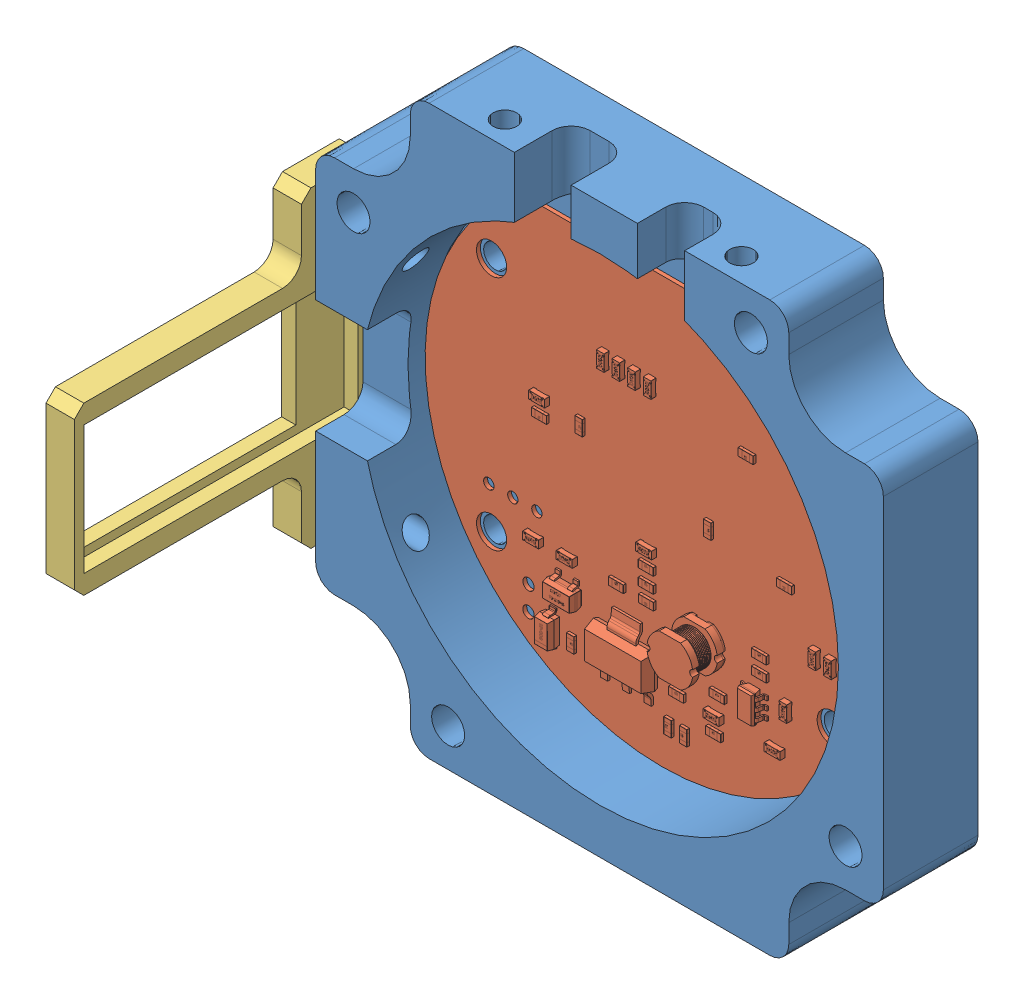
SolidWorks assembly sensor, configuration 默认. Lengths in mm.
Overall size (63 60 35.5).
3 component instances, 3 part files, 6 mates.
Components (placement in the parent):
- sensor-shield-1: sensor-shield [默认] at (-34.5724 32.0232 50) size (60 60 10)
- servo-sensor-1: servo-sensor [默认] at (-4.5724 2.023 53) x (-1 0 0) z (0 0 -1) size (50.04 44.96 3.91)
- LCD_shield-1: LCD_shield [默认] at (-34.5724 10.8232 85.5) x (0 -1 0) z (-1 0 0) size (33 32 3)
Mates (geometry in assembly coordinates):
- 同心1: concentric aligned: cylinder of sensor-shield-1 through (-4.5724 2.0232 52) axis (0 0 1) radius 25.25; cylinder of servo-sensor-1 through (-4.5724 2.0232 53.4115) axis (0 0 1) radius 25.0192
- 平行1: parallel aligned: plane of sensor-shield-1 through (-34.5724 32.0232 60) normal (0 1 0); plane of servo-sensor-1 through (-19.6854 21.962 53.4115) normal (0 1 0)
- 重合2: coincident anti-aligned: plane of sensor-shield-1 through (-22.5724 14.5232 53) normal (0 0 1); plane of servo-sensor-1 through (-4.5724 2.6813 53) normal (0 0 -1)
- 距离1: distance = 21.2 mm aligned: plane of sensor-shield-1 through (-34.5724 32.0232 60) normal (0 1 0); plane of LCD_shield-1 through (-37.5724 10.8232 85.5) normal (0 1 0)
- 重合4: coincident anti-aligned: plane of sensor-shield-1 through (-34.5724 32.0232 60) normal (-1 0 0); plane of LCD_shield-1 through (-34.5724 10.8232 85.5) normal (1 0 0)
- 距离3: distance = 6.5 mm anti-aligned: plane of LCD_shield-1 through (-37.5724 18.5232 53.5) normal (0 0 -1); plane of sensor-shield-1 through (-34.5724 32.0232 60) normal (0 0 1)
